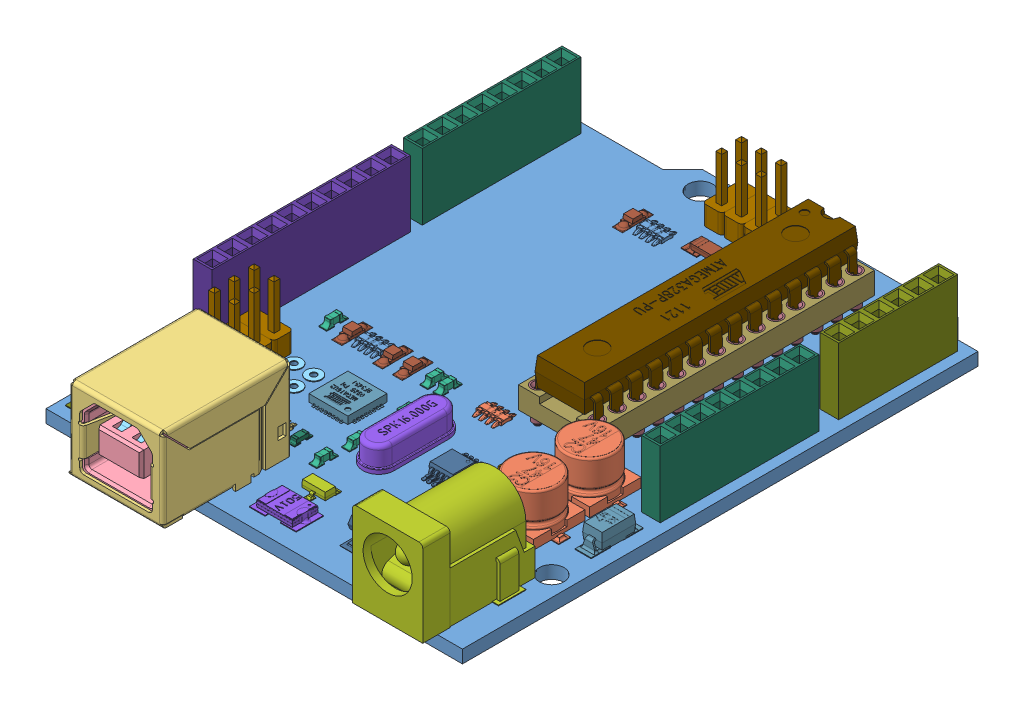
SolidWorks assembly arduino uno, configuration Default. Lengths in mm.
Overall size (53.34 15.25 74.97).
87 component instances, 35 part files, 133 mates.
Components (placement in the parent):
- unoboard blue-1: unoboard blue [Default] at origin size (53.34 1.65 68.58)
- 47uf CAP Dcase-1: 47uf CAP Dcase [Default] at (-9.4141 0 -18.4991) x (0 0 -1) z (1 0 0) size (6.6 5.81 8)
- USB type b-1: USB type b [Default] at (-38.02 0.43 6.35) size (14.34 15.2 16.54)
  - USB SHELL-1: USB SHELL [Default] at origin size (14.34 15.2 16.54)
  - USB core-1: USB core [Default] at origin size (11.3 10.68 15.75)
  - usb top contact-1: usb top contact [Default] at (1.25 6.09 -0.38) size (1 9.67 13.76)
  - usb btm contact-1: usb btm contact [Default] at (1.25 4.41 -0.38) size (1 6.84 11.76)
  - usb btm contact-2: usb btm contact [Default] at (-1.25 4.41 -0.38) size (1 6.84 11.76)
  - usb top contact-2: usb top contact [Default] at (-1.25 6.09 -0.38) size (1 9.67 13.76)
- power jack-1: power jack [Default] at (-7.675 0 1.905) size (11.2 15.2 15.9)
- 47uf CAP Dcase-2: 47uf CAP Dcase [Default] at (-9.4141 0 -25.7132) x (0 0 -1) z (1 0 0) size (6.6 5.81 8)
- crystal-1: crystal [Default] at (-26.162 0 -18.923) x (1 0 0) z (0 0 -1) size (4 5 11)
- 2pin_header__02-1: 2pin_header__02 [Default] at (-46.23 0 -15.75) size (5 11.75 2.54)
- nano - reg-1: nano - reg [Default] at (-17.399 0 -7.747) size (6.5 1.69 8.3)
- led-1: led [Default] at (-34.29 0 -27.94) x (0 0 1) z (-1 0 0) size (4 0.86 1.35)
- 2pin_header__02-2: 2pin_header__02 [Default] at (-30.43 0 -64.91) x (0 0 1) z (-1 0 0) size (5 11.75 2.54)
- dip28-1: dip28 [Default] at (-16.383 1.5 -46.355) x (0 0 -1) z (1 0 0) size (35.48 7.37 10.1)
  - dip28-1: dip28 [Default] at origin size (35.48 2.8 10.1)
  - dip socket pin-1: dip socket pin [Default] at (16.51 2.8 -3.81) size (1.7 7.37 1.7)
  - dip socket pin-2: dip socket pin [Default] at (16.51 2.8 3.81) size (1.7 7.37 1.7)
  - dip socket pin-3: dip socket pin [Default] at (13.97 2.8 -3.81) size (1.7 7.37 1.7)
  - dip socket pin-4: dip socket pin [Default] at (13.97 2.8 3.81) size (1.7 7.37 1.7)
  - dip socket pin-5: dip socket pin [Default] at (11.43 2.8 -3.81) size (1.7 7.37 1.7)
  - dip socket pin-6: dip socket pin [Default] at (11.43 2.8 3.81) size (1.7 7.37 1.7)
  - dip socket pin-7: dip socket pin [Default] at (8.89 2.8 -3.81) size (1.7 7.37 1.7)
  - dip socket pin-8: dip socket pin [Default] at (8.89 2.8 3.81) size (1.7 7.37 1.7)
  - dip socket pin-9: dip socket pin [Default] at (6.35 2.8 -3.81) size (1.7 7.37 1.7)
  - dip socket pin-10: dip socket pin [Default] at (6.35 2.8 3.81) size (1.7 7.37 1.7)
  - dip socket pin-11: dip socket pin [Default] at (3.81 2.8 -3.81) size (1.7 7.37 1.7)
  - dip socket pin-12: dip socket pin [Default] at (3.81 2.8 3.81) size (1.7 7.37 1.7)
  - dip socket pin-13: dip socket pin [Default] at (1.27 2.8 -3.81) size (1.7 7.37 1.7)
  - dip socket pin-14: dip socket pin [Default] at (1.27 2.8 3.81) size (1.7 7.37 1.7)
  - dip socket pin-15: dip socket pin [Default] at (-1.27 2.8 -3.81) size (1.7 7.37 1.7)
  - dip socket pin-16: dip socket pin [Default] at (-1.27 2.8 3.81) size (1.7 7.37 1.7)
  - dip socket pin-17: dip socket pin [Default] at (-3.81 2.8 -3.81) size (1.7 7.37 1.7)
  - dip socket pin-18: dip socket pin [Default] at (-3.81 2.8 3.81) size (1.7 7.37 1.7)
  - dip socket pin-19: dip socket pin [Default] at (-6.35 2.8 -3.81) size (1.7 7.37 1.7)
  - dip socket pin-20: dip socket pin [Default] at (-6.35 2.8 3.81) size (1.7 7.37 1.7)
  - dip socket pin-21: dip socket pin [Default] at (-8.89 2.8 -3.81) size (1.7 7.37 1.7)
  - dip socket pin-22: dip socket pin [Default] at (-8.89 2.8 3.81) size (1.7 7.37 1.7)
  - dip socket pin-23: dip socket pin [Default] at (-11.43 2.8 -3.81) size (1.7 7.37 1.7)
  - dip socket pin-24: dip socket pin [Default] at (-11.43 2.8 3.81) size (1.7 7.37 1.7)
  - dip socket pin-25: dip socket pin [Default] at (-13.97 2.8 -3.81) size (1.7 7.37 1.7)
  - dip socket pin-26: dip socket pin [Default] at (-13.97 2.8 3.81) size (1.7 7.37 1.7)
  - dip socket pin-27: dip socket pin [Default] at (-16.51 2.8 -3.81) size (1.7 7.37 1.7)
  - dip socket pin-28: dip socket pin [Default] at (-16.51 2.8 3.81) size (1.7 7.37 1.7)
- 2pin_header__02-3: 2pin_header__02 [Default] at (-27.89 0 -64.91) x (0 0 1) z (-1 0 0) size (5 11.75 2.54)
- 2pin_header__02-4: 2pin_header__02 [Default] at (-25.35 0 -64.91) x (0 0 1) z (-1 0 0) size (5 11.75 2.54)
- 2pin_header__02-5: 2pin_header__02 [Default] at (-46.23 0 -18.29) size (5 11.75 2.54)
- 2pin_header__02-6: 2pin_header__02 [Default] at (-46.23 0 -20.83) size (5 11.75 2.54)
- atmega16u2-1: atmega16u2 [Default] at (-34.671 0.06 -20) x (1 0 0) z (0 0 -1) size (5.5 1.01 5.5)
- led-2: led [Default] at (-36.83 0 -27.94) x (0 0 1) z (-1 0 0) size (4 0.86 1.35)
- led-3: led [Default] at (-42.037 0 -27.94) x (0 0 1) z (-1 0 0) size (4 0.86 1.35)
- led-4: led [Default] at (-36.576 0 -58.42) x (0 0 1) z (-1 0 0) size (4 0.86 1.35)
- 8 PORT HEADER-3: 8 PORT HEADER [Default] at (-50.8 0 -45.72) x (0 0 -1) z (1 0 0) size (20.32 10.51 2.41)
- 8 PORT HEADER-4: 8 PORT HEADER [Default] at (-2.54 0 -27.94) x (0 0 -1) z (1 0 0) size (20.32 10.51 2.41)
- 6 PORT HEADER-3: 6 PORT HEADER [Default] at (-2.54 0 -50.8) x (0 0 -1) z (1 0 0) size (15.24 10.51 2.41)
- 10 PORT HEADER-1: 10 PORT HEADER [Default] at (-50.8 0 -18.796) x (0 0 -1) z (1 0 0) size (25.4 10.51 2.41)
- ATMEL328P-1: ATMEL328P [Default] at (-16.383 4.3 -46.355) x (0 0 -1) z (1 0 0) size (35 7.27 7.87)
- 102 RESISTOR PACK-1: 102 RESISTOR PACK [Default] at (-33.782 0 -58.42) size (3.2 0.46 3)
- 102 RESISTOR PACK-2: 102 RESISTOR PACK [Default] at (-39.37 0 -27.94) size (3.2 0.46 3)
- 103 RESISTOR PACK-3: 103 RESISTOR PACK [Default] at (-23.876 0 -27.94) size (3.2 0.46 3)
- 220 RESISTOR PACK-1: 220 RESISTOR PACK [Default] at (-36.83 0 -12.827) size (3.2 0.46 3)
- 16mhz crystal - measured-1: 16mhz crystal - measured [Default] at (-24.892 0 -41.275) x (0 0 -1) z (1 0 0) size (3.4 0.8 2)
- PADS001-1: PADS001 [Default] at (-39.878 0.1 -18.288) x (-1 0 0) z (0 0 1) size (4.54 0.1 4.54)
- 603 cap on pad-1: 603 cap on pad [Default] at (-44.45 0 -27.94) x (0 0 -1) z (1 0 0) size (2.76 0.9 1.12)
- ssot3-1: ssot3 [Default] at (-26.5 0 -8.128) x (-1 0 0) z (0 0 -1) size (3 1.13 3.09)
- mf-msmf050-2-1: mf-msmf050-2 [Default] at (-26.5 0 -4.064) size (5.77 1.02 3.72)
- 603 cap on pad-2: 603 cap on pad [Default] at (-29.845 0 -27.94) x (0 0 -1) z (1 0 0) size (2.76 0.9 1.12)
- 603 cap on pad-3: 603 cap on pad [Default] at (-31.496 0 -27.94) x (0 0 -1) z (1 0 0) size (2.76 0.9 1.12)
- lmv358-1: lmv358 [Default] at (-15.24 0 -21.971) x (0 0 -1) z (1 0 0) size (3.7 1.4 2.9)
- 603 cap on pad-4: 603 cap on pad [Default] at (-15.24 0 -18.415) size (2.76 0.9 1.12)
- 603 cap on pad-5: 603 cap on pad [Default] at (-29.845 0 -12.065) x (0 0 1) z (-1 0 0) size (2.76 0.9 1.12)
- 603 cap on pad-6: 603 cap on pad [Default] at (-29.591 0 -22.352) x (0 0 1) z (-1 0 0) size (2.76 0.9 1.12)
- 603 cap on pad-7: 603 cap on pad [Default] at (-29.591 0 -16.002) x (0 0 1) z (-1 0 0) size (2.76 0.9 1.12)
- 603 cap on pad-8: 603 cap on pad [Default] at (-41.91 0 -12.7) x (0 0 1) z (-1 0 0) size (2.76 0.9 1.12)
- lp2985dgkr-1: lp2985dgkr [Default] at (-20.32 0 -19.05) x (0 0 -1) z (1 0 0) size (5.85 1.1 3)
- cd1206 diode-1: cd1206 diode [Default] at (-27.94 0 -59.436) x (0 0 -1) z (1 0 0) size (2.07 0.96 5)
- cd1206 diode-2: cd1206 diode [Default] at (-46.228 0 -13.081) x (0 0 1) z (-1 0 0) size (2.07 0.96 5)
- 603 resistor-1: 603 resistor [Default] at (-29.591 0 -19.05) x (0 0 1) z (-1 0 0) size (2.36 0.61 1.03)
- blm21-1: blm21 [Default] at (-45.085 0 -7.62) x (0 0 -1) z (1 0 0) size (2.76 0.95 1.32)
- m7 diode-1: m7 diode [Default] at (-2.794 0 -21.59) x (0 0 -1) z (1 0 0) size (6.66 2.35 2.5)
- MLC0603-1: MLC0603 [Default] at (-33.655 0 -12.827) x (0 0 -1) z (1 0 0) size (2.36 0.6 1.03)
- MLC0603-2: MLC0603 [Default] at (-39.37 0 -12.827) x (0 0 -1) z (1 0 0) size (2.36 0.6 1.03)
- RESET BUTTON-1: RESET BUTTON [Default] at (-49.403 0 -6.35) size (6.2 3.1 9.6)
  - RESET CORE-1: RESET CORE [Default] at (0 0.1 0) x (-1 0 0) z (0 0 -1) size (6.2 3.1 9.6)
  - RESET-1: RESET [Default] at (0 0.1 0) x (0 0 1) z (-1 0 0) size (7.3 2 6.2)
Mates (geometry in assembly coordinates):
- Distance1: distance = 1.905 mm aligned: plane of power jack-1 through (-7.675 0 1.905) normal (0 0 1); plane of unoboard blue-1 through (0 0 0) normal (0 0 1)
- Coincident2: coincident aligned: plane of unoboard blue-1 through (0 0 0) normal (0 1 0); plane of power jack-1 through (-7.675 0 1.905) normal (0 1 0)
- Coincident3: coincident anti-aligned: plane of unoboard blue-1 through (0 0 0) normal (0 1 0); plane of USB type b-1/USB core-1 through (-38.02 0 6.35) normal (0 -1 0)
- Distance2: distance = 6.35 mm aligned: plane of USB type b-1/USB SHELL-1 through (-38.02 0.43 6.35) normal (0 0 1); plane of unoboard blue-1 through (0 0 0) normal (0 0 1)
- Coincident5: coincident aligned: plane of unoboard blue-1 through (0 0 0) normal (0 1 0); plane of 47uf CAP Dcase-1 through (-9.4141 0 -18.4991) normal (0 1 0)
- Parallel1: parallel anti-aligned: plane of unoboard blue-1 through (0 0 0) normal (0 0 1); plane of 47uf CAP Dcase-1 through (-9.4141 0 -18.4991) normal (0 0 -1)
- Coincident7: coincident aligned: plane of 47uf CAP Dcase-1 through (-6.1141 1.5 -15.1991) normal (1 0 0); plane of 47uf CAP Dcase-2 through (-6.1141 1.5 -22.4132) normal (1 0 0)
- Coincident8: coincident anti-aligned: plane of unoboard blue-1 through (0 0 0) normal (0 1 0); plane of 47uf CAP Dcase-2 through (-8.1891 0 -25.7132) normal (0 -1 0)
- Distance3: distance = 3.175 mm aligned: plane of power jack-1 through (-3.175 10.5 -1.595) normal (1 0 0); plane of unoboard blue-1 through (0 -1.65 0) normal (1 0 0)
- Distance4: distance = 32 mm aligned: plane of USB type b-1/USB SHELL-1 through (-32 0.43 6.35) normal (1 0 0); plane of unoboard blue-1 through (0 -1.65 0) normal (1 0 0)
- Coincident11: coincident anti-aligned: plane of unoboard blue-1 through (0 0 0) normal (0 1 0); plane of crystal-1 through (-26.162 0 -22.423) normal (0 -1 0)
- Concentric1: concentric aligned: cylinder of unoboard blue-1 through (-26.162 -10 -16.383) axis (0 1 0) radius 0.5; cylinder of crystal-1 through (-26.162 -2 -16.383) axis (0 1 0) radius 0.4
- Concentric2: concentric aligned: cylinder of unoboard blue-1 through (-26.162 -10 -21.463) axis (0 1 0) radius 0.5; cylinder of crystal-1 through (-26.162 -2 -21.463) axis (0 1 0) radius 0.4
- Coincident12: coincident anti-aligned: plane of unoboard blue-1 through (0 0 0) normal (0 1 0); plane of 2pin_header__02-1 through (-44.23 0 -14.98) normal (0 -1 0)
- Distance5: distance = 15.75 mm aligned: plane of 2pin_header__02-1 through (-46.23 0 -15.75) normal (0 0 1); plane of assembly through (0 0 0) normal (0 0 1)
- Distance6: distance = 46.23 mm aligned: plane of 2pin_header__02-1 through (-46.23 0 -15.75) normal (1 0 0); plane of assembly through (0 0 0) normal (1 0 0)
- Coincident15: coincident anti-aligned: plane of unoboard blue-1 through (0 0 0) normal (0 1 0); plane of 2pin_header__02-2 through (-31.2 0 -62.91) normal (0 -1 0)
- Distance7: distance = 64.91 mm aligned: plane of 2pin_header__02-2 through (-30.43 0 -64.91) normal (0 0 1); plane of assembly through (0 0 0) normal (0 0 1)
- Distance8: distance = 30.43 mm anti-aligned: plane of 2pin_header__02-2 through (-30.43 0 -64.91) normal (-1 0 0); plane of assembly through (0 0 0) normal (1 0 0)
- Coincident19: coincident anti-aligned: plane of unoboard blue-1 through (0 0 0) normal (0 1 0); plane of nano - reg-1 through (-17.399 0 -7.747) normal (0 -1 0)
- Concentric3: concentric aligned: cylinder of unoboard blue-1 through (-20.193 -10 -62.865) axis (0 1 0) radius 0.4; cylinder of dip28-1/dip socket pin-1 through (-20.193 33.2926 -62.865) axis (0 1 0) radius 0.25
- Concentric4: concentric aligned: cylinder of unoboard blue-1 through (-12.573 -10 -29.845) axis (0 1 0) radius 0.4; cylinder of dip28-1/dip socket pin-28 through (-12.573 33.2926 -29.845) axis (0 1 0) radius 0.25
- Distance9: distance = 1.5 mm anti-aligned: plane of dip28-1/dip28-1 through (-11.333 1.5 -64.095) normal (0 -1 0); plane of unoboard blue-1 through (0 0 0) normal (0 1 0)
- Coincident21: coincident anti-aligned: plane of unoboard blue-1 through (0 0 0) normal (0 1 0); plane of atmega16u2-1 through (-34.671 0 -20) normal (0 -1 0)
- Distance10: distance = 20 mm anti-aligned: plane of atmega16u2-1 through (-34.671 0.06 -20) normal (0 0 -1); plane of unoboard blue-1 through (0 0 0) normal (0 0 1)
- Distance11: distance = 34.671 mm aligned: plane of atmega16u2-1 through (-34.671 0.06 -20) normal (1 0 0); plane of unoboard blue-1 through (0 0 0) normal (1 0 0)
- Coincident25: coincident anti-aligned: plane of unoboard blue-1 through (0 0 0) normal (0 1 0); plane of led-1 through (-34.29 0 -28.94) normal (0 -1 0)
- Distance12: distance = 34.29 mm anti-aligned: plane of led-1 through (-34.29 0 -27.94) normal (-1 0 0); plane of unoboard blue-1 through (0 0 0) normal (1 0 0)
- Distance13: distance = 27.94 mm aligned: plane of led-1 through (-34.29 0 -27.94) normal (0 0 1); plane of unoboard blue-1 through (0 0 0) normal (0 0 1)
- Coincident28: coincident aligned: plane of led-2 through (-36.83 0 -28.94) normal (0 -1 0); plane of led-3 through (-42.037 0 -28.94) normal (0 -1 0)
- Coincident29: coincident aligned: plane of led-1 through (-34.29 0 -27.94) normal (0 0 1); plane of led-2 through (-36.83 0 -27.94) normal (0 0 1)
- Coincident30: coincident aligned: plane of led-1 through (-34.29 0 -27.94) normal (0 0 1); plane of led-3 through (-42.037 0 -27.94) normal (0 0 1)
- Distance14: distance = 2.54 mm aligned: plane of led-2 through (-36.83 0 -27.94) normal (-1 0 0); plane of led-1 through (-34.29 0 -27.94) normal (-1 0 0)
- Coincident32: coincident anti-aligned: plane of unoboard blue-1 through (0 0 0) normal (0 1 0); plane of led-2 through (-36.83 0 -28.94) normal (0 -1 0)
- Distance15: distance = 42.037 mm anti-aligned: plane of led-3 through (-42.037 0 -27.94) normal (-1 0 0); plane of unoboard blue-1 through (0 0 0) normal (1 0 0)
- Coincident34: coincident anti-aligned: plane of unoboard blue-1 through (0 0 0) normal (0 1 0); plane of led-4 through (-36.576 0 -59.42) normal (0 -1 0)
- Distance16: distance = 36.576 mm anti-aligned: plane of led-4 through (-36.576 0 -58.42) normal (-1 0 0); plane of unoboard blue-1 through (0 0 0) normal (1 0 0)
- Distance17: distance = 58.42 mm aligned: plane of led-4 through (-36.576 0 -58.42) normal (0 0 1); plane of unoboard blue-1 through (0 0 0) normal (0 0 1)
- Coincident37: coincident aligned: plane of unoboard blue-1 through (0 0 0) normal (0 1 0); plane of 8 PORT HEADER-4 through (-2.54 0 -27.94) normal (0 1 0)
- Coincident38: coincident aligned: plane of unoboard blue-1 through (0 0 0) normal (0 1 0); plane of 8 PORT HEADER-3 through (-50.8 0 -45.72) normal (0 1 0)
- Parallel2: parallel aligned: plane of unoboard blue-1 through (0 0 0) normal (1 0 0); plane of 8 PORT HEADER-4 through (-2.54 0 -27.94) normal (1 0 0)
- Parallel3: parallel aligned: plane of unoboard blue-1 through (0 0 0) normal (1 0 0); plane of 8 PORT HEADER-3 through (-50.8 0 -45.72) normal (1 0 0)
- Concentric5: concentric aligned: cylinder of unoboard blue-1 through (-2.54 -1.65 -27.94) axis (0 1 0) radius 0.4; line of 8 PORT HEADER-4 through (-2.54 -2.5255 -27.94) axis (0 1 0)
- Concentric6: concentric aligned: cylinder of unoboard blue-1 through (-50.8 -1.65 -45.72) axis (0 1 0) radius 0.4; line of 8 PORT HEADER-3 through (-50.8 -2.5255 -45.72) axis (0 1 0)
- Coincident43: coincident aligned: plane of unoboard blue-1 through (0 0 0) normal (0 1 0); plane of 10 PORT HEADER-1 through (-50.8 0 -18.796) normal (0 1 0)
- Coincident44: coincident aligned: plane of unoboard blue-1 through (0 0 0) normal (0 1 0); plane of 6 PORT HEADER-3 through (-2.54 0 -50.8) normal (0 1 0)
- Parallel4: parallel aligned: plane of unoboard blue-1 through (0 0 0) normal (1 0 0); plane of 6 PORT HEADER-3 through (-2.54 0 -50.8) normal (1 0 0)
- Parallel5: parallel aligned: plane of unoboard blue-1 through (0 0 0) normal (1 0 0); plane of 10 PORT HEADER-1 through (-50.8 0 -18.796) normal (1 0 0)
- Concentric7: concentric aligned: cylinder of unoboard blue-1 through (-50.8 -1.65 -18.796) axis (0 1 0) radius 0.4; line of 10 PORT HEADER-1 through (-50.8 -2.5255 -18.796) axis (0 1 0)
- Concentric9: concentric aligned: cylinder of unoboard blue-1 through (-2.54 -1.65 -50.8) axis (0 1 0) radius 0.4; line of 6 PORT HEADER-3 through (-2.54 -2.5255 -50.8) axis (0 1 0)
- Coincident50: coincident aligned: plane of dip28-1/dip28-1 through (-16.383 1.5 -46.355) normal (0 0 -1); plane of ATMEL328P-1 through (-16.383 4.3 -46.355) normal (0 0 -1)
- Coincident51: coincident aligned: plane of dip28-1/dip28-1 through (-16.383 1.5 -46.355) normal (1 0 0); plane of ATMEL328P-1 through (-16.383 4.3 -46.355) normal (1 0 0)
- Coincident52: coincident aligned: plane of dip28-1/dip28-1 through (-11.333 4.3 -64.095) normal (0 1 0); plane of ATMEL328P-1 through (-16.383 4.3 -46.355) normal (0 1 0)
- Distance18: distance = 7.747 mm: plane of nano - reg-1 through (-17.399 0 -7.747) normal (0 0 1); line of unoboard blue-1 through (-53.34 0 0) axis (1 0 0)
- Distance19: distance = 17.399 mm aligned: plane of nano - reg-1 through (-17.399 0 -7.747) normal (1 0 0); plane of unoboard blue-1 through (0 0 0) normal (1 0 0)
- Coincident55: coincident anti-aligned: plane of unoboard blue-1 through (0 0 0) normal (0 1 0); plane of 102 RESISTOR PACK-1 through (-33.982 0 -59.12) normal (0 -1 0)
- Distance20: distance = 33.782 mm aligned: plane of 102 RESISTOR PACK-1 through (-33.782 0 -58.42) normal (1 0 0); plane of unoboard blue-1 through (0 0 0) normal (1 0 0)
- Distance21: distance = 58.42 mm aligned: plane of 102 RESISTOR PACK-1 through (-33.782 0 -58.42) normal (0 0 1); plane of unoboard blue-1 through (0 0 0) normal (0 0 1)
- Coincident58: coincident aligned: plane of 102 RESISTOR PACK-2 through (-39.37 0 -27.94) normal (0 1 0); plane of 103 RESISTOR PACK-3 through (-23.876 0 -27.94) normal (0 1 0)
- Coincident59: coincident aligned: plane of unoboard blue-1 through (0 0 0) normal (0 1 0); plane of 103 RESISTOR PACK-3 through (-23.876 0 -27.94) normal (0 1 0)
- Coincident60: coincident aligned: plane of 102 RESISTOR PACK-2 through (-39.37 0 -27.94) normal (0 0 1); plane of 103 RESISTOR PACK-3 through (-23.876 0 -27.94) normal (0 0 1)
- Distance22: distance = 23.876 mm aligned: plane of 103 RESISTOR PACK-3 through (-23.876 0 -27.94) normal (1 0 0); plane of unoboard blue-1 through (0 0 0) normal (1 0 0)
- Distance23: distance = 39.37 mm aligned: plane of 102 RESISTOR PACK-2 through (-39.37 0 -27.94) normal (1 0 0); plane of unoboard blue-1 through (0 0 0) normal (1 0 0)
- Distance24: distance = 27.94 mm aligned: plane of 102 RESISTOR PACK-2 through (-39.37 0 -27.94) normal (0 0 1); plane of unoboard blue-1 through (0 0 0) normal (0 0 1)
- Distance25: distance = 12.827 mm aligned: plane of 220 RESISTOR PACK-1 through (-36.83 0 -12.827) normal (0 0 1); plane of unoboard blue-1 through (0 0 0) normal (0 0 1)
- Distance26: distance = 36.83 mm aligned: plane of 220 RESISTOR PACK-1 through (-36.83 0 -12.827) normal (1 0 0); plane of unoboard blue-1 through (0 0 0) normal (1 0 0)
- Coincident66: coincident aligned: plane of unoboard blue-1 through (0 0 0) normal (0 1 0); plane of 220 RESISTOR PACK-1 through (-36.83 0 -12.827) normal (0 1 0)
- Coincident67: coincident anti-aligned: plane of unoboard blue-1 through (0 0 0) normal (0 1 0); plane of 16mhz crystal - measured-1 through (-24.892 0 -41.275) normal (0 -1 0)
- Distance27: distance = 41.275 mm anti-aligned: plane of 16mhz crystal - measured-1 through (-24.892 0 -41.275) normal (0 0 -1); plane of unoboard blue-1 through (0 0 0) normal (0 0 1)
- Distance28: distance = 24.892 mm aligned: plane of 16mhz crystal - measured-1 through (-24.892 0 -41.275) normal (1 0 0); plane of unoboard blue-1 through (0 0 0) normal (1 0 0)
- Coincident70: coincident anti-aligned: plane of unoboard blue-1 through (0 0 0) normal (0 1 0); plane of PADS001-1 through (-42.418 0 -18.288) normal (0 -1 0)
- Distance29: distance = 18.288 mm aligned: plane of PADS001-1 through (-39.878 0.1 -18.288) normal (0 0 1); plane of unoboard blue-1 through (0 0 0) normal (0 0 1)
- Distance30: distance = 39.878 mm anti-aligned: plane of PADS001-1 through (-39.878 0.1 -18.288) normal (-1 0 0); plane of unoboard blue-1 through (0 0 0) normal (1 0 0)
- Distance31: distance = 4.064 mm aligned: plane of mf-msmf050-2-1 through (-26.5 0 -4.064) normal (0 0 1); plane of unoboard blue-1 through (0 0 0) normal (0 0 1)
- Distance32: distance = 26.5 mm aligned: plane of mf-msmf050-2-1 through (-26.5 0 -4.064) normal (1 0 0); plane of unoboard blue-1 through (0 0 0) normal (1 0 0)
- Coincident72: coincident aligned: plane of unoboard blue-1 through (0 0 0) normal (0 1 0); plane of mf-msmf050-2-1 through (-26.5 0 -4.064) normal (0 1 0)
- Distance33: distance = 8.128 mm anti-aligned: plane of unoboard blue-1 through (0 0 0) normal (0 0 1); plane of ssot3-1 through (-26.5 0 -8.128) normal (0 0 -1)
- Coincident74: coincident anti-aligned: plane of ssot3-1 through (-26.5 0 -8.128) normal (-1 0 0); plane of mf-msmf050-2-1 through (-26.5 0 -4.064) normal (1 0 0)
- Coincident75: coincident aligned: plane of unoboard blue-1 through (0 0 0) normal (0 1 0); plane of ssot3-1 through (-26.5 0 -8.128) normal (0 1 0)
- Coincident76: coincident anti-aligned: plane of led-1 through (-34.29 0 -27.94) normal (0 0 1); plane of 603 cap on pad-1 through (-44.45 0 -27.94) normal (0 0 -1)
- Coincident77: coincident aligned: plane of unoboard blue-1 through (0 0 0) normal (0 1 0); plane of 603 cap on pad-1 through (-44.45 0 -27.94) normal (0 1 0)
- Distance34: distance = 44.45 mm aligned: plane of 603 cap on pad-1 through (-44.45 0 -27.94) normal (1 0 0); plane of unoboard blue-1 through (0 0 0) normal (1 0 0)
- Coincident79: coincident aligned: plane of 603 cap on pad-2 through (-29.845 0 -27.94) normal (0 1 0); plane of 603 cap on pad-3 through (-31.496 0 -27.94) normal (0 1 0)
- Coincident80: coincident aligned: plane of 603 cap on pad-2 through (-29.845 0 -27.94) normal (0 0 -1); plane of 603 cap on pad-3 through (-31.496 0 -27.94) normal (0 0 -1)
- Coincident81: coincident aligned: plane of unoboard blue-1 through (0 0 0) normal (0 1 0); plane of 603 cap on pad-2 through (-29.845 0 -27.94) normal (0 1 0)
- Coincident82: coincident aligned: plane of 603 cap on pad-1 through (-44.45 0 -27.94) normal (0 0 -1); plane of 603 cap on pad-2 through (-29.845 0 -27.94) normal (0 0 -1)
- Distance36: distance = 29.845 mm aligned: plane of 603 cap on pad-2 through (-29.845 0 -27.94) normal (1 0 0); plane of unoboard blue-1 through (0 0 0) normal (1 0 0)
- Distance37: distance = 31.496 mm aligned: plane of 603 cap on pad-3 through (-31.496 0 -27.94) normal (1 0 0); plane of unoboard blue-1 through (0 0 0) normal (1 0 0)
- Distance38: distance = 15.24 mm aligned: plane of unoboard blue-1 through (0 0 0) normal (1 0 0); plane of lmv358-1 through (-15.24 0 -21.971) normal (1 0 0)
- Distance39: distance = 21.971 mm anti-aligned: plane of lmv358-1 through (-15.24 0 -21.971) normal (0 0 -1); plane of unoboard blue-1 through (0 0 0) normal (0 0 1)
- Coincident88: coincident aligned: plane of unoboard blue-1 through (0 0 0) normal (0 1 0); plane of lmv358-1 through (-15.24 0 -21.971) normal (0 1 0)
- Distance40: distance = 18.415 mm aligned: plane of 603 cap on pad-4 through (-15.24 0 -18.415) normal (0 0 1); plane of unoboard blue-1 through (0 0 0) normal (0 0 1)
- Distance41: distance = 15.24 mm aligned: plane of 603 cap on pad-4 through (-15.24 0 -18.415) normal (1 0 0); plane of unoboard blue-1 through (0 0 0) normal (1 0 0)
- Coincident91: coincident aligned: plane of unoboard blue-1 through (0 0 0) normal (0 1 0); plane of 603 cap on pad-4 through (-15.24 0 -18.415) normal (0 1 0)
- Coincident92: coincident aligned: plane of unoboard blue-1 through (0 0 0) normal (0 1 0); plane of 603 cap on pad-7 through (-29.591 0 -16.002) normal (0 1 0)
- Coincident93: coincident aligned: plane of unoboard blue-1 through (0 0 0) normal (0 1 0); plane of 603 cap on pad-6 through (-29.591 0 -22.352) normal (0 1 0)
- Coincident94: coincident aligned: plane of 603 cap on pad-5 through (-29.845 0 -12.065) normal (0 1 0); plane of unoboard blue-1 through (0 0 0) normal (0 1 0)
- Coincident95: coincident aligned: plane of 603 cap on pad-8 through (-41.91 0 -12.7) normal (0 1 0); plane of unoboard blue-1 through (0 0 0) normal (0 1 0)
- Coincident96: coincident aligned: plane of 603 cap on pad-7 through (-29.591 0 -16.002) normal (-1 0 0); plane of 603 cap on pad-6 through (-29.591 0 -22.352) normal (-1 0 0)
- Distance42: distance = 29.591 mm anti-aligned: plane of 603 cap on pad-7 through (-29.591 0 -16.002) normal (-1 0 0); plane of unoboard blue-1 through (0 0 0) normal (1 0 0)
- Distance43: distance = 22.352 mm: plane of 603 cap on pad-6 through (-29.591 0 -22.352) normal (0 0 1); line of unoboard blue-1 through (-53.34 0 0) axis (1 0 0)
- Distance44: distance = 16.002 mm aligned: plane of 603 cap on pad-7 through (-29.591 0 -16.002) normal (0 0 1); plane of unoboard blue-1 through (0 0 0) normal (0 0 1)
- Distance45: distance = 29.845 mm anti-aligned: plane of 603 cap on pad-5 through (-29.845 0 -12.065) normal (-1 0 0); plane of unoboard blue-1 through (0 0 0) normal (1 0 0)
- Distance46: distance = 12.065 mm aligned: plane of 603 cap on pad-5 through (-29.845 0 -12.065) normal (0 0 1); plane of unoboard blue-1 through (0 0 0) normal (0 0 1)
- Distance47: distance = 41.91 mm anti-aligned: plane of 603 cap on pad-8 through (-41.91 0 -12.7) normal (-1 0 0); plane of unoboard blue-1 through (0 0 0) normal (1 0 0)
- Distance48: distance = 12.7 mm aligned: plane of 603 cap on pad-8 through (-41.91 0 -12.7) normal (0 0 1); plane of unoboard blue-1 through (0 0 0) normal (0 0 1)
- Distance49: distance = 20.32 mm aligned: plane of lp2985dgkr-1 through (-20.32 0 -19.05) normal (1 0 0); plane of unoboard blue-1 through (0 0 0) normal (1 0 0)
- Distance50: distance = 19.05 mm anti-aligned: plane of lp2985dgkr-1 through (-20.32 0 -19.05) normal (0 0 -1); plane of unoboard blue-1 through (0 0 0) normal (0 0 1)
- Coincident99: coincident aligned: plane of unoboard blue-1 through (0 0 0) normal (0 1 0); plane of lp2985dgkr-1 through (-20.32 0 -19.05) normal (0 1 0)
- Distance51: distance = 27.94 mm aligned: plane of cd1206 diode-1 through (-27.94 0 -59.436) normal (1 0 0); plane of unoboard blue-1 through (0 0 0) normal (1 0 0)
- Distance52: distance = 59.436 mm anti-aligned: plane of cd1206 diode-1 through (-27.94 0 -59.436) normal (0 0 -1); plane of unoboard blue-1 through (0 0 0) normal (0 0 1)
- Coincident102: coincident aligned: plane of unoboard blue-1 through (0 0 0) normal (0 1 0); plane of cd1206 diode-1 through (-27.94 0 -59.436) normal (0 1 0)
- Distance53: distance = 46.228 mm anti-aligned: plane of cd1206 diode-2 through (-46.228 0 -13.081) normal (-1 0 0); plane of unoboard blue-1 through (0 0 0) normal (1 0 0)
- Distance54: distance = 13.081 mm aligned: plane of unoboard blue-1 through (0 0 0) normal (0 0 1); plane of cd1206 diode-2 through (-46.228 0 -13.081) normal (0 0 1)
- Coincident105: coincident aligned: plane of unoboard blue-1 through (0 0 0) normal (0 1 0); plane of cd1206 diode-2 through (-46.228 0 -13.081) normal (0 1 0)
- Distance55: distance = 29.591 mm anti-aligned: plane of 603 resistor-1 through (-29.591 0 -19.05) normal (-1 0 0); plane of unoboard blue-1 through (0 0 0) normal (1 0 0)
- Distance56: distance = 19.05 mm aligned: plane of 603 resistor-1 through (-29.591 0 -19.05) normal (0 0 1); plane of unoboard blue-1 through (0 0 0) normal (0 0 1)
- Coincident108: coincident aligned: plane of unoboard blue-1 through (0 0 0) normal (0 1 0); plane of 603 resistor-1 through (-29.591 0 -19.05) normal (0 1 0)
- Distance57: distance = 7.62 mm anti-aligned: plane of blm21-1 through (-45.085 0 -7.62) normal (0 0 -1); plane of unoboard blue-1 through (0 0 0) normal (0 0 1)
- Distance58: distance = 45.085 mm aligned: plane of blm21-1 through (-45.085 0 -7.62) normal (1 0 0); plane of unoboard blue-1 through (0 0 0) normal (1 0 0)
- Distance59: distance = 21.59 mm anti-aligned: plane of m7 diode-1 through (-2.794 0 -21.59) normal (0 0 -1); plane of unoboard blue-1 through (0 0 0) normal (0 0 1)
- Distance60: distance = 2.794 mm aligned: plane of m7 diode-1 through (-2.794 0 -21.59) normal (1 0 0); plane of unoboard blue-1 through (0 0 0) normal (1 0 0)
- Coincident113: coincident aligned: plane of unoboard blue-1 through (0 0 0) normal (0 1 0); plane of m7 diode-1 through (-2.794 0 -21.59) normal (0 1 0)
- Coincident114: coincident anti-aligned: plane of 220 RESISTOR PACK-1 through (-36.83 0 -12.827) normal (0 0 1); plane of MLC0603-1 through (-33.655 0 -12.827) normal (0 0 -1)
- Distance61: distance = 33.655 mm aligned: plane of MLC0603-1 through (-33.655 0 -12.827) normal (1 0 0); plane of unoboard blue-1 through (0 0 0) normal (1 0 0)
- Coincident115: coincident aligned: plane of unoboard blue-1 through (0 0 0) normal (0 1 0); plane of MLC0603-1 through (-33.655 0 -12.827) normal (0 1 0)
- Coincident116: coincident aligned: plane of unoboard blue-1 through (0 0 0) normal (0 1 0); plane of blm21-1 through (-45.085 0 -7.62) normal (0 1 0)
- Coincident117: coincident anti-aligned: plane of 220 RESISTOR PACK-1 through (-36.83 0 -12.827) normal (0 0 1); plane of MLC0603-2 through (-39.37 0 -12.827) normal (0 0 -1)
- Coincident118: coincident aligned: plane of unoboard blue-1 through (0 0 0) normal (0 1 0); plane of MLC0603-2 through (-39.37 0 -12.827) normal (0 1 0)
- Distance62: distance = 39.37 mm aligned: plane of MLC0603-2 through (-39.37 0 -12.827) normal (1 0 0); plane of unoboard blue-1 through (0 0 0) normal (1 0 0)
- Distance63: distance = 49.403 mm aligned: plane of RESET BUTTON-1 through (-49.403 0 -6.35) normal (1 0 0); plane of unoboard blue-1 through (0 0 0) normal (1 0 0)
- Distance64: distance = 6.35 mm aligned: plane of RESET BUTTON-1; plane of unoboard blue-1 through (0 0 0) normal (0 0 1)
- Coincident122: coincident aligned: plane of unoboard blue-1 through (0 0 0) normal (0 1 0); plane of RESET BUTTON-1 through (-49.403 0 -6.35) normal (0 1 0)
